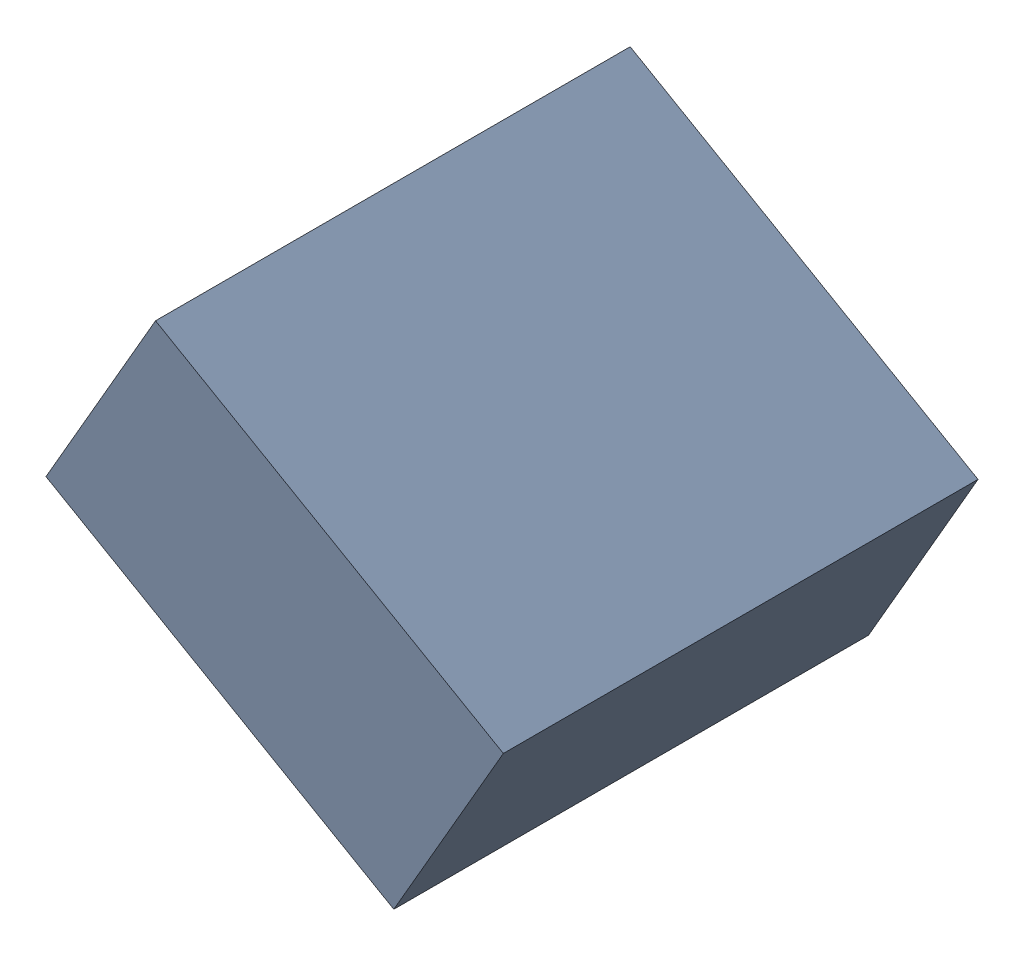
SolidWorks assembly C23_TDA6, configuration Standard. Lengths in mm.
Overall size (1.25 1.07 1.3).
2 component instances, 1 part files, 0 mates.
Components (placement in the parent):
- 885543056-1: 885543056 [Standard] at (-41.0166 31.3495 0) size (1.25 1.07 1.3)
  - Extruded_23-1: Extruded_23 [Standard] at origin size (1.25 1.07 1.3)
